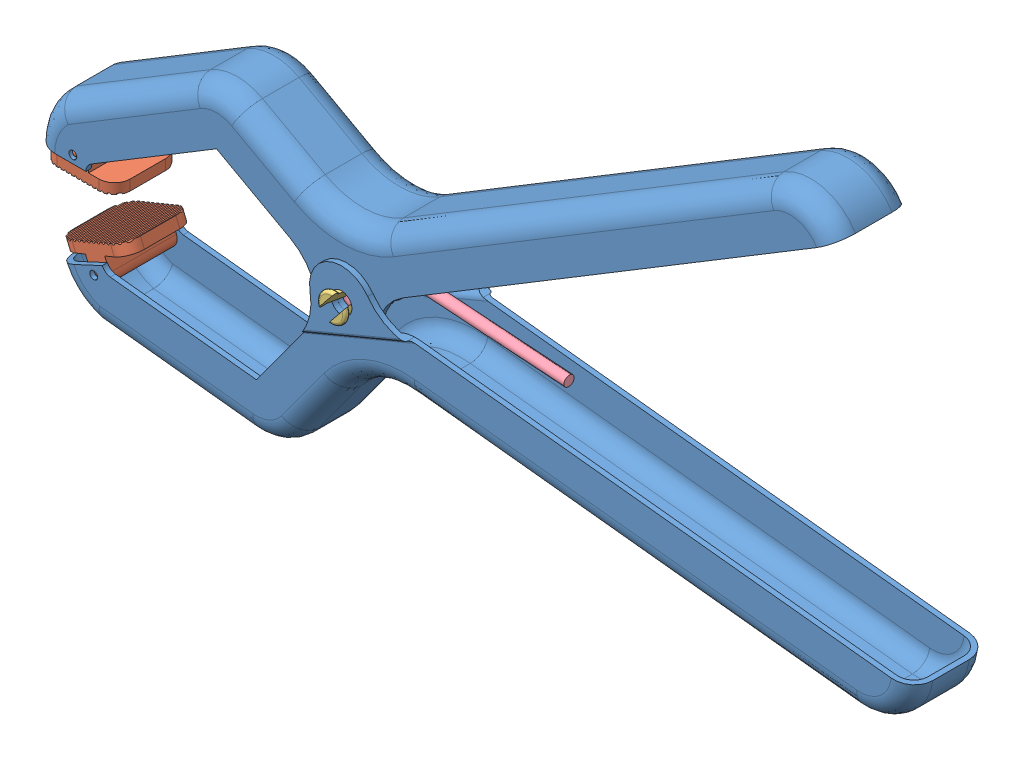
SolidWorks assembly Assem1, configuration Default. Lengths in mm.
Overall size (170.41 140.91 19.75).
6 component instances, 4 part files, 7 mates.
Components (placement in the parent):
- klemmen lijmklem-1: klemmen lijmklem [Default] at (-12.1337 56.8132 101.3262) size (153.56 66.76 15.45)
- kussentje klem-1: kussentje klem [Default] at (-4.6439 53.8064 108.9262) x (0 0 -1) z (1 0 0) size (14.3 6.55 14)
- buisje lijmklem-1: buisje lijmklem [Default] at (47.8663 60.5123 118.3334) x (0.627922 0.778276 0) z (-0.778276 0.627922 0) size (5.99 19.75 5.99)
- klemmen lijmklem-3: klemmen lijmklem [dik] at (-8.0792 38.5171 116.3262) x (0.906379 0.422466 0) z (0 0 -1) size (153.56 66.76 17.17)
- kussentje klem-2: kussentje klem [Default] at (-2.3524 44.46 108.7262) x (0 0 1) z (0.923801 0.382872 0) size (14.3 6.55 14)
- veer lijmklem-4: veer lijmklem [Default] at (48.0174 60.6958 114.5442) x (0.525691 -0.850154 0.029799) z (0.850625 0.524955 -0.029311) size (23.97 13 33.68)
Mates (geometry in assembly coordinates):
- Coincident3: coincident: plane of klemmen lijmklem-1 through (0.2798 56.8132 115.3262) normal (0 0 -1); plane of kussentje klem-1 through (-8.6439 55.8064 115.3262) normal (0 0 1)
- Concentric5: concentric: cylinder of klemmen lijmklem-1 through (47.8663 60.5123 101.3262) axis (0 0 1) radius 2; cylinder of buisje lijmklem-1 through (47.8663 60.5123 118.3334) axis (0 0 1) radius 2
- Concentric6: concentric: cylinder of buisje lijmklem-1 through (47.8663 60.5123 118.3334) axis (0 0 1) radius 2; cylinder of klemmen lijmklem-3 through (47.8663 60.5123 120.3262) axis (0 0 -1) radius 2
- Coincident6: coincident: plane of klemmen lijmklem-1 through (0.2798 56.8132 101.3262) normal (0 0 -1); plane of klemmen lijmklem-3 through (32.0099 57.4958 101.3262) normal (0 0 1)
- Coincident7: coincident: plane of klemmen lijmklem-3 through (3.1722 43.7614 102.3262) normal (0 0 1); plane of kussentje klem-2 through (-5.2819 41.0809 102.3262) normal (0 0 -1)
- Lock2: lock: unknown of klemmen lijmklem-3; unknown of kussentje klem-2
- Coincident10: coincident: plane of buisje lijmklem-1 through (49.1222 62.0688 100.3262) normal (0 0 1); plane of klemmen lijmklem-3 through (32.0099 57.4958 100.3262) normal (0 0 -1)
